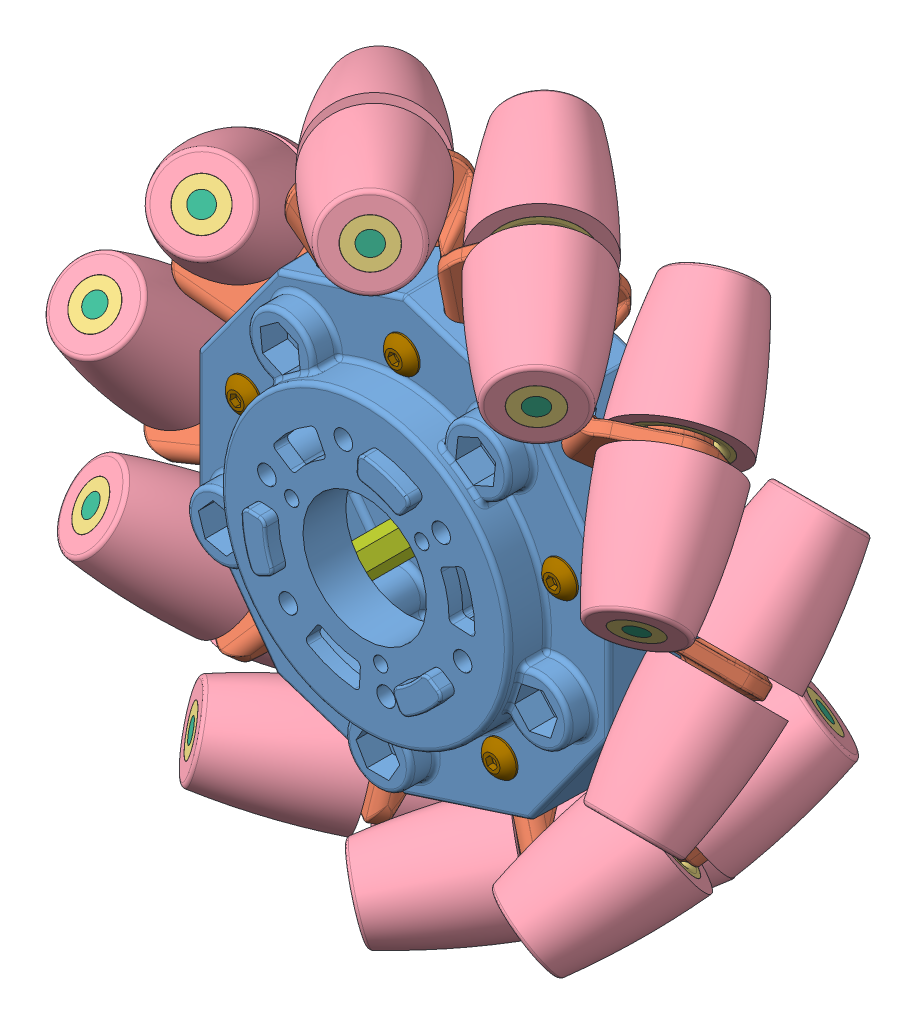
SolidWorks assembly 6in mecanum wheel Vex 217-2586, configuration Default. Lengths in mm.
Overall size (159.68 163.12 66.52).
98 component instances, 9 part files, 0 mates.
Components (placement in the parent):
- 217-2586-001 Rev4-1: 217-2586-001 Rev4 [Default] at (0 0 -6.35) size (95.78 100.46 28.55)
- 217-2586-001 Rev4-2: 217-2586-001 Rev4 [Default] at (0 0 6.35) x (-0.809017 0.587785 0) z (0 0 -1) size (95.78 100.46 28.55)
- 217-2586-002 Rev2-1: 217-2586-002 Rev2 [Default] at (-12.8179 39.4495 0) x (0.951057 0.309017 0) z (-0.309017 0.951057 0) size (26.84 25.28 30.09)
- 217-2586-003 Rev2-1: 217-2586-003 Rev2 [Default] at (-23.0486 57.9718 -4.0062) x (0.656917 0.263835 -0.706294) z (-0.340891 0.939492 0.033887) size (19.46 28.57 19.46)
- 217-2586-003 Rev2-2: 217-2586-003 Rev2 [Default] at (-15.4283 60.4478 4.0062) x (-0.134846 0.975606 -0.173232) z (0.72771 -0.021148 -0.685559) size (19.46 28.57 19.46)
- 217-2586-004 Rev1-1: 217-2586-004 Rev1 [Default] at (-19.6233 59.0847 -0.4047) x (0.203589 -0.97318 0.107105) z (-0.711546 -0.071932 0.698948) size (25.9 28.58 25.9)
- 217-2586-004 Rev1-2: 217-2586-004 Rev1 [Default] at (-18.8527 59.3351 0.4056) x (-0.440555 -0.64952 0.619705) z (0.594691 -0.72827 -0.340537) size (25.9 28.58 25.9)
- 217-2586-005 Rev2-1: 217-2586-005 Rev2 [Default] at (-25.2573 57.2541 -6.3286) x (0.672499 0.218508 0.707107) z (-0.568604 -0.459036 0.682624) size (8.5 8 8)
- 217-2586-005 Rev2-2: 217-2586-005 Rev2 [Default] at (-13.2196 61.1654 6.3286) x (0.672499 0.218508 0.707107) z (-0.568604 -0.459036 0.682624) size (8.5 8 8)
- 217-2586-007 Rev1-1: 217-2586-007 Rev1 [Default] at (-19.2384 59.2098 0) x (0.672499 0.218508 0.707107) z (-0.649691 0.631892 0.422627) size (61.72 5 5)
- 217-2586-008 Rev1-1: 217-2586-008 Rev1 [Default] at (-17.6961 -15.9337 -0.127) x (-0.309017 -0.951057 0) z (0 0 -1) size (7.33 6.35 31.75)
- NUT-832-NYLOCK-1: NUT-832-NYLOCK [Default] at (-36.6157 11.8972 -13.6563) x (-0.997378 -0.072366 0) z (0.072366 -0.997378 0) size (10.2 5.86 8.12)
- SCREW-832-1250-1: SCREW-832-1250 [Default] at (-36.6157 11.8972 14.9098) x (0 0 -1) z (-0.996377 0.08505 0) size (33.96 7.92 7.92)
- NUT-832-NYLOCK-2: NUT-832-NYLOCK [Default] at (0 38.5 -13.6563) x (-0.377031 0.926201 0) z (-0.926201 -0.377031 0) size (10.2 5.86 8.12)
- NUT-832-NYLOCK-3: NUT-832-NYLOCK [Default] at (36.6157 11.8972 -13.6563) x (0.76436 0.644789 0) z (-0.644789 0.76436 0) size (10.2 5.86 8.12)
- NUT-832-NYLOCK-4: NUT-832-NYLOCK [Default] at (22.6297 -31.1472 -13.6563) x (0.849431 -0.527699 0) z (0.527699 0.849431 0) size (10.2 5.86 8.12)
- NUT-832-NYLOCK-5: NUT-832-NYLOCK [Default] at (-22.6297 -31.1472 -13.6563) x (-0.239383 -0.970925 0) z (0.970925 -0.239383 0) size (10.2 5.86 8.12)
- SCREW-832-1250-2: SCREW-832-1250 [Default] at (0 38.5 14.9098) x (0 0 -1) z (-0.22701 0.973892 0) size (33.96 7.92 7.92)
- SCREW-832-1250-3: SCREW-832-1250 [Default] at (36.6157 11.8972 14.9098) x (0 0 -1) z (0.856077 0.516849 0) size (33.96 7.92 7.92)
- SCREW-832-1250-4: SCREW-832-1250 [Default] at (22.6297 -31.1472 14.9098) x (0 0 -1) z (0.756095 -0.654462 0) size (33.96 7.92 7.92)
- SCREW-832-1250-5: SCREW-832-1250 [Default] at (-22.6297 -31.1472 14.9098) x (0 0 -1) z (-0.388785 -0.921329 0) size (33.96 7.92 7.92)
- 217-2586-002 Rev2-2: 217-2586-002 Rev2 [Default] at (12.8179 39.4495 0) x (0.951057 -0.309017 0) z (0.309017 0.951057 0) size (26.84 25.28 30.09)
- 217-2586-002 Rev2-3: 217-2586-002 Rev2 [Default] at (33.5577 24.3811 0) x (0.587785 -0.809017 0) z (0.809017 0.587785 0) size (26.84 25.28 30.09)
- 217-2586-002 Rev2-4: 217-2586-002 Rev2 [Default] at (41.4796 0 0) x (0 -1 0) z (1 0 0) size (26.84 25.28 30.09)
- 217-2586-002 Rev2-5: 217-2586-002 Rev2 [Default] at (33.5577 -24.3811 0) x (-0.587785 -0.809017 0) z (0.809017 -0.587785 0) size (26.84 25.28 30.09)
- 217-2586-002 Rev2-6: 217-2586-002 Rev2 [Default] at (12.8179 -39.4495 0) x (-0.951057 -0.309017 0) z (0.309017 -0.951057 0) size (26.84 25.28 30.09)
- 217-2586-002 Rev2-7: 217-2586-002 Rev2 [Default] at (-12.8179 -39.4495 0) x (-0.951057 0.309017 0) z (-0.309017 -0.951057 0) size (26.84 25.28 30.09)
- 217-2586-002 Rev2-8: 217-2586-002 Rev2 [Default] at (-33.5577 -24.3811 0) x (-0.587785 0.809017 0) z (-0.809017 -0.587785 0) size (26.84 25.28 30.09)
- 217-2586-002 Rev2-9: 217-2586-002 Rev2 [Default] at (-41.4796 0 0) x (0 1 0) z (-1 0 0) size (26.84 25.28 30.09)
- 217-2586-002 Rev2-10: 217-2586-002 Rev2 [Default] at (-33.5577 24.3811 0) x (0.587785 0.809017 0) z (-0.809017 0.587785 0) size (26.84 25.28 30.09)
- 217-2586-004 Rev1-3: 217-2586-004 Rev1 [Default] at (19.6242 59.0844 0.4056) x (-0.738195 -0.266521 0.619705) z (0.053049 -0.938733 -0.340537) size (25.9 28.58 25.9)
- 217-2586-004 Rev1-4: 217-2586-004 Rev1 [Default] at (50.6053 36.2655 0.4056) x (-0.75387 0.21828 0.619705) z (-0.508857 -0.790633 -0.340537) size (25.9 28.58 25.9)
- 217-2586-004 Rev1-5: 217-2586-004 Rev1 [Default] at (62.2568 -0.4056 0.4056) x (-0.481592 0.619705 0.619705) z (-0.876396 -0.340537 -0.340537) size (25.9 28.58 25.9)
- 217-2586-004 Rev1-6: 217-2586-004 Rev1 [Default] at (50.1284 -36.9218 0.4056) x (-0.025362 0.784425 0.619705) z (-0.909182 0.239632 -0.340537) size (25.9 28.58 25.9)
- 217-2586-004 Rev1-7: 217-2586-004 Rev1 [Default] at (18.8527 -59.3351 0.4056) x (0.440555 0.64952 0.619705) z (-0.594691 0.72827 -0.340537) size (25.9 28.58 25.9)
- 217-2586-004 Rev1-8: 217-2586-004 Rev1 [Default] at (-19.6242 -59.0844 0.4056) x (0.738195 0.266521 0.619705) z (-0.053049 0.938733 -0.340537) size (25.9 28.58 25.9)
- 217-2586-004 Rev1-9: 217-2586-004 Rev1 [Default] at (-50.6053 -36.2655 0.4056) x (0.75387 -0.21828 0.619705) z (0.508857 0.790633 -0.340537) size (25.9 28.58 25.9)
- 217-2586-004 Rev1-10: 217-2586-004 Rev1 [Default] at (-62.2568 0.4056 0.4056) x (0.481592 -0.619705 0.619705) z (0.876396 0.340537 -0.340537) size (25.9 28.58 25.9)
- 217-2586-004 Rev1-11: 217-2586-004 Rev1 [Default] at (-50.1284 36.9218 0.4056) x (0.025362 -0.784425 0.619705) z (0.909182 -0.239632 -0.340537) size (25.9 28.58 25.9)
- 217-2586-008 Rev1-2: 217-2586-008 Rev1 [Default] at (-22.647 7.3585 -0.127) x (-0.978148 -0.207912 0) z (0 0 -1) size (7.33 6.35 31.75)
- 217-2586-008 Rev1-3: 217-2586-008 Rev1 [Default] at (-4.9509 23.2921 -0.127) x (-0.669131 0.743145 0) z (0 0 -1) size (7.33 6.35 31.75)
- 217-2586-008 Rev1-4: 217-2586-008 Rev1 [Default] at (17.6961 15.9337 -0.127) x (0.309017 0.951057 0) z (0 0 -1) size (7.33 6.35 31.75)
- 217-2586-008 Rev1-5: 217-2586-008 Rev1 [Default] at (22.647 -7.3585 -0.127) x (0.978148 0.207912 0) z (0 0 -1) size (7.33 6.35 31.75)
- 217-2586-008 Rev1-6: 217-2586-008 Rev1 [Default] at (4.9509 -23.2921 -0.127) x (0.669131 -0.743145 0) z (0 0 -1) size (7.33 6.35 31.75)
- 217-2586-005 Rev2-3: 217-2586-005 Rev2 [Default] at (25.2573 57.2541 6.3286) x (0.672499 -0.218508 0.707107) z (-0.729825 -0.037151 0.682624) size (8.5 8 8)
- 217-2586-005 Rev2-4: 217-2586-005 Rev2 [Default] at (54.0867 31.4737 6.3286) x (0.415627 -0.572061 0.707107) z (-0.612278 0.398924 0.682624) size (8.5 8 8)
- 217-2586-005 Rev2-5: 217-2586-005 Rev2 [Default] at (62.2568 -6.3286 6.3286) x (0 -0.707107 0.707107) z (-0.260861 0.682624 0.682624) size (8.5 8 8)
- 217-2586-005 Rev2-6: 217-2586-005 Rev2 [Default] at (46.647 -41.7136 6.3286) x (-0.415627 -0.572061 0.707107) z (0.190195 0.705585 0.682624) size (8.5 8 8)
- 217-2586-005 Rev2-7: 217-2586-005 Rev2 [Default] at (13.2196 -61.1654 6.3286) x (-0.672499 -0.218508 0.707107) z (0.568604 0.459036 0.682624) size (8.5 8 8)
- 217-2586-005 Rev2-8: 217-2586-005 Rev2 [Default] at (-25.2573 -57.2541 6.3286) x (-0.672499 0.218508 0.707107) z (0.729825 0.037151 0.682624) size (8.5 8 8)
- 217-2586-005 Rev2-9: 217-2586-005 Rev2 [Default] at (-54.0867 -31.4737 6.3286) x (-0.415627 0.572061 0.707107) z (0.612278 -0.398924 0.682624) size (8.5 8 8)
- 217-2586-005 Rev2-10: 217-2586-005 Rev2 [Default] at (-62.2568 6.3286 6.3286) x (0 0.707107 0.707107) z (0.260861 -0.682624 0.682624) size (8.5 8 8)
- 217-2586-005 Rev2-11: 217-2586-005 Rev2 [Default] at (-46.647 41.7136 6.3286) x (0.415627 0.572061 0.707107) z (-0.190195 -0.705585 0.682624) size (8.5 8 8)
- 217-2586-005 Rev2-12: 217-2586-005 Rev2 [Default] at (13.2196 61.1654 -6.3286) x (0.672499 -0.218508 0.707107) z (-0.729825 -0.037151 0.682624) size (8.5 8 8)
- 217-2586-005 Rev2-13: 217-2586-005 Rev2 [Default] at (46.647 41.7136 -6.3286) x (0.415627 -0.572061 0.707107) z (-0.612278 0.398924 0.682624) size (8.5 8 8)
- 217-2586-005 Rev2-14: 217-2586-005 Rev2 [Default] at (62.2568 6.3286 -6.3286) x (0 -0.707107 0.707107) z (-0.260861 0.682624 0.682624) size (8.5 8 8)
- 217-2586-005 Rev2-15: 217-2586-005 Rev2 [Default] at (54.0867 -31.4737 -6.3286) x (-0.415627 -0.572061 0.707107) z (0.190195 0.705585 0.682624) size (8.5 8 8)
- 217-2586-005 Rev2-16: 217-2586-005 Rev2 [Default] at (25.2573 -57.2541 -6.3286) x (-0.672499 -0.218508 0.707107) z (0.568604 0.459036 0.682624) size (8.5 8 8)
- 217-2586-005 Rev2-17: 217-2586-005 Rev2 [Default] at (-13.2196 -61.1654 -6.3286) x (-0.672499 0.218508 0.707107) z (0.729825 0.037151 0.682624) size (8.5 8 8)
- 217-2586-005 Rev2-18: 217-2586-005 Rev2 [Default] at (-46.647 -41.7136 -6.3286) x (-0.415627 0.572061 0.707107) z (0.612278 -0.398924 0.682624) size (8.5 8 8)
- 217-2586-005 Rev2-19: 217-2586-005 Rev2 [Default] at (-62.2568 -6.3286 -6.3286) x (0 0.707107 0.707107) z (0.260861 -0.682624 0.682624) size (8.5 8 8)
- 217-2586-005 Rev2-20: 217-2586-005 Rev2 [Default] at (-54.0867 31.4737 -6.3286) x (0.415627 0.572061 0.707107) z (-0.190195 -0.705585 0.682624) size (8.5 8 8)
- 217-2586-003 Rev2-3: 217-2586-003 Rev2 [Default] at (23.0486 57.9718 4.0062) x (0.464354 0.868542 -0.173232) z (0.5763 -0.444846 -0.685559) size (19.46 28.57 19.46)
- 217-2586-003 Rev2-4: 217-2586-003 Rev2 [Default] at (52.7216 33.3525 4.0062) x (0.886187 0.429725 -0.173232) z (0.204762 -0.698629 -0.685559) size (19.46 28.57 19.46)
- 217-2586-003 Rev2-5: 217-2586-003 Rev2 [Default] at (62.2568 -4.0062 4.0062) x (0.969526 -0.173232 -0.173232) z (-0.244988 -0.685559 -0.685559) size (19.46 28.57 19.46)
- 217-2586-003 Rev2-6: 217-2586-003 Rev2 [Default] at (48.012 -39.8348 4.0062) x (0.68254 -0.710021 -0.173232) z (-0.60116 -0.410628 -0.685559) size (19.46 28.57 19.46)
- 217-2586-003 Rev2-7: 217-2586-003 Rev2 [Default] at (15.4283 -60.4478 4.0062) x (0.134846 -0.975606 -0.173232) z (-0.72771 0.021148 -0.685559) size (19.46 28.57 19.46)
- 217-2586-003 Rev2-8: 217-2586-003 Rev2 [Default] at (-23.0486 -57.9718 4.0062) x (-0.464354 -0.868542 -0.173232) z (-0.5763 0.444846 -0.685559) size (19.46 28.57 19.46)
- 217-2586-003 Rev2-9: 217-2586-003 Rev2 [Default] at (-52.7216 -33.3525 4.0062) x (-0.886187 -0.429725 -0.173232) z (-0.204762 0.698629 -0.685559) size (19.46 28.57 19.46)
- 217-2586-003 Rev2-10: 217-2586-003 Rev2 [Default] at (-62.2568 4.0062 4.0062) x (-0.969526 0.173232 -0.173232) z (0.244988 0.685559 -0.685559) size (19.46 28.57 19.46)
- 217-2586-003 Rev2-11: 217-2586-003 Rev2 [Default] at (-48.012 39.8348 4.0062) x (-0.68254 0.710021 -0.173232) z (0.60116 0.410628 -0.685559) size (19.46 28.57 19.46)
- 217-2586-004 Rev1-12: 217-2586-004 Rev1 [Default] at (18.8536 59.3348 -0.4047) x (-0.407314 -0.906986 0.107105) z (-0.617933 0.360042 0.698948) size (25.9 28.58 25.9)
- 217-2586-004 Rev1-13: 217-2586-004 Rev1 [Default] at (50.129 36.921 -0.4047) x (-0.862637 -0.494354 0.107105) z (-0.288291 0.654492 0.698948) size (25.9 28.58 25.9)
- 217-2586-004 Rev1-14: 217-2586-004 Rev1 [Default] at (62.2568 0.4047 -0.4047) x (-0.988462 0.107105 0.107105) z (0.151469 0.698948 0.698948) size (25.9 28.58 25.9)
- 217-2586-004 Rev1-15: 217-2586-004 Rev1 [Default] at (50.6047 -36.2663 -0.4047) x (-0.736728 0.667653 0.107105) z (0.533372 0.47643 0.698948) size (25.9 28.58 25.9)
- 217-2586-004 Rev1-16: 217-2586-004 Rev1 [Default] at (19.6233 -59.0847 -0.4047) x (-0.203589 0.97318 0.107105) z (0.711546 0.071932 0.698948) size (25.9 28.58 25.9)
- 217-2586-004 Rev1-17: 217-2586-004 Rev1 [Default] at (-18.8536 -59.3348 -0.4047) x (0.407314 0.906986 0.107105) z (0.617933 -0.360042 0.698948) size (25.9 28.58 25.9)
- 217-2586-004 Rev1-18: 217-2586-004 Rev1 [Default] at (-50.129 -36.921 -0.4047) x (0.862637 0.494354 0.107105) z (0.288291 -0.654492 0.698948) size (25.9 28.58 25.9)
- 217-2586-004 Rev1-19: 217-2586-004 Rev1 [Default] at (-62.2568 -0.4047 -0.4047) x (0.988462 -0.107105 0.107105) z (-0.151469 -0.698948 0.698948) size (25.9 28.58 25.9)
- 217-2586-004 Rev1-20: 217-2586-004 Rev1 [Default] at (-50.6047 36.2663 -0.4047) x (0.736728 -0.667653 0.107105) z (-0.533372 -0.47643 0.698948) size (25.9 28.58 25.9)
- 217-2586-003 Rev2-12: 217-2586-003 Rev2 [Default] at (15.4283 60.4478 -4.0062) x (0.686535 -0.172679 -0.706294) z (0.276433 0.960435 0.033887) size (19.46 28.57 19.46)
- 217-2586-003 Rev2-13: 217-2586-003 Rev2 [Default] at (48.012 39.8348 -4.0062) x (0.45392 -0.543235 -0.706294) z (0.788169 0.614525 0.033887) size (19.46 28.57 19.46)
- 217-2586-003 Rev2-14: 217-2586-003 Rev2 [Default] at (62.2568 4.0062 -4.0062) x (0.047924 -0.706294 -0.706294) z (0.998851 0.033887 0.033887) size (19.46 28.57 19.46)
- 217-2586-003 Rev2-15: 217-2586-003 Rev2 [Default] at (52.7216 -33.3525 -4.0062) x (-0.376378 -0.599573 -0.706294) z (0.828006 -0.559695 0.033887) size (19.46 28.57 19.46)
- 217-2586-003 Rev2-16: 217-2586-003 Rev2 [Default] at (23.0486 -57.9718 -4.0062) x (-0.656917 -0.263835 -0.706294) z (0.340891 -0.939492 0.033887) size (19.46 28.57 19.46)
- 217-2586-003 Rev2-17: 217-2586-003 Rev2 [Default] at (-15.4283 -60.4478 -4.0062) x (-0.686535 0.172679 -0.706294) z (-0.276433 -0.960435 0.033887) size (19.46 28.57 19.46)
- 217-2586-003 Rev2-18: 217-2586-003 Rev2 [Default] at (-48.012 -39.8348 -4.0062) x (-0.45392 0.543235 -0.706294) z (-0.788169 -0.614525 0.033887) size (19.46 28.57 19.46)
- 217-2586-003 Rev2-19: 217-2586-003 Rev2 [Default] at (-62.2568 -4.0062 -4.0062) x (-0.047924 0.706294 -0.706294) z (-0.998851 -0.033887 0.033887) size (19.46 28.57 19.46)
- 217-2586-003 Rev2-20: 217-2586-003 Rev2 [Default] at (-52.7216 33.3525 -4.0062) x (0.376378 0.599573 -0.706294) z (-0.828006 0.559695 0.033887) size (19.46 28.57 19.46)
- 217-2586-007 Rev1-2: 217-2586-007 Rev1 [Default] at (19.2384 59.2098 0) x (0.672499 -0.218508 0.707107) z (-0.154194 0.89309 0.422627) size (61.72 5 5)
- 217-2586-007 Rev1-3: 217-2586-007 Rev1 [Default] at (50.3668 36.5937 0) x (0.415627 -0.572061 0.707107) z (0.4002 0.813158 0.422627) size (61.72 5 5)
- 217-2586-007 Rev1-4: 217-2586-007 Rev1 [Default] at (62.2568 0 0) x (0 -0.707107 0.707107) z (0.801731 0.422627 0.422627) size (61.72 5 5)
- 217-2586-007 Rev1-5: 217-2586-007 Rev1 [Default] at (50.3668 -36.5937 0) x (-0.415627 -0.572061 0.707107) z (0.897028 -0.129333 0.422627) size (61.72 5 5)
- 217-2586-007 Rev1-6: 217-2586-007 Rev1 [Default] at (19.2384 -59.2098 0) x (-0.672499 -0.218508 0.707107) z (0.649691 -0.631892 0.422627) size (61.72 5 5)
- 217-2586-007 Rev1-7: 217-2586-007 Rev1 [Default] at (-19.2384 -59.2098 0) x (-0.672499 0.218508 0.707107) z (0.154194 -0.89309 0.422627) size (61.72 5 5)
- 217-2586-007 Rev1-8: 217-2586-007 Rev1 [Default] at (-50.3668 -36.5937 0) x (-0.415627 0.572061 0.707107) z (-0.4002 -0.813158 0.422627) size (61.72 5 5)
- 217-2586-007 Rev1-9: 217-2586-007 Rev1 [Default] at (-62.2568 0 0) x (0 0.707107 0.707107) z (-0.801731 -0.422627 0.422627) size (61.72 5 5)
- 217-2586-007 Rev1-10: 217-2586-007 Rev1 [Default] at (-50.3668 36.5937 0) x (0.415627 0.572061 0.707107) z (-0.897028 0.129333 0.422627) size (61.72 5 5)
